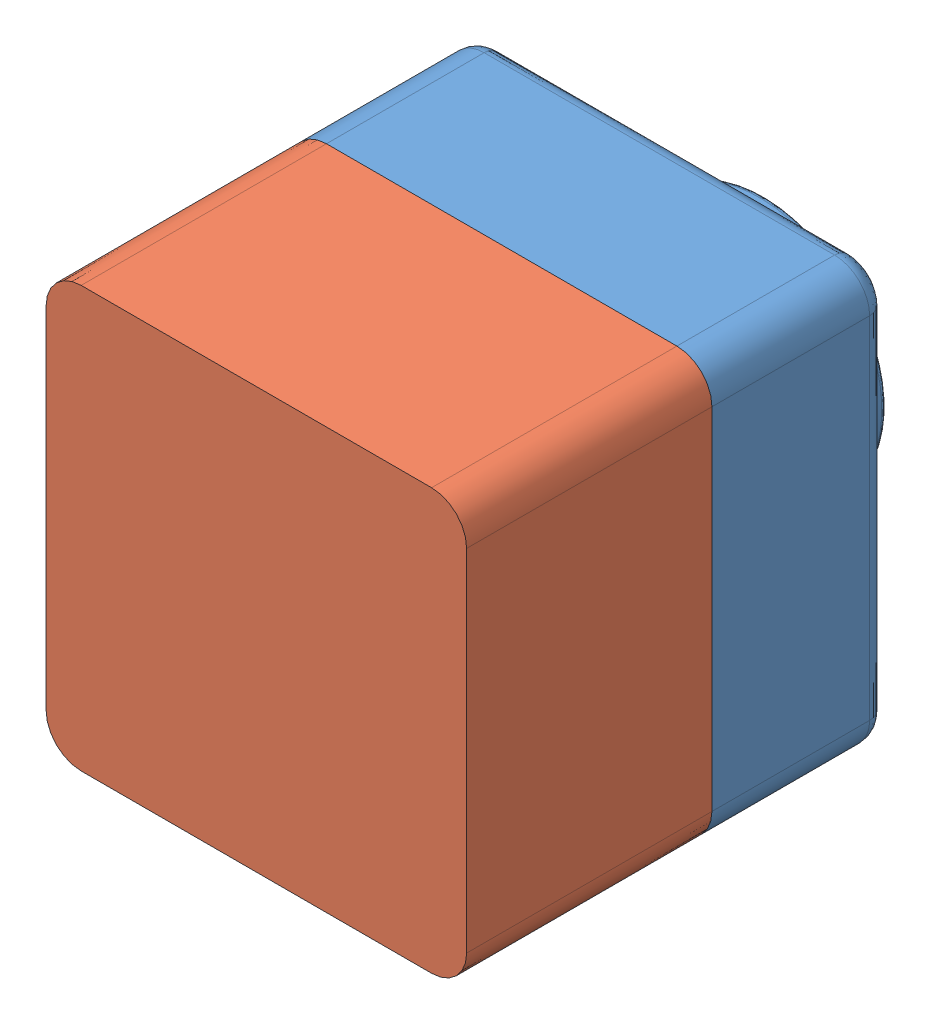
SolidWorks assembly Assem1, configuration Default. Lengths in mm.
Overall size (120 120 145).
2 component instances, 2 part files, 3 mates.
Components (placement in the parent):
- Part1-1: Part1 [Default] at (1.3944 79.59 90.9836) size (120 120 75)
- part2-2: part2 [Default] at (4.8079 98.2333 210.9836) x (-1 0 0) z (0 0 -1) size (120 120 90)
Mates (geometry in assembly coordinates):
- Coincident3: coincident: plane of Part1-1 through (-58.6056 137.59 140.9836) normal (0 -1 0); plane of part2-2 through (-48.6056 137.59 140.9836) normal (0 1 0)
- Coincident4: coincident: plane of Part1-1 through (-56.6056 139.59 140.9836) normal (1 0 0); plane of part2-2 through (-56.6056 29.59 140.9836) normal (-1 0 0)
- Coincident5: coincident anti-aligned: plane of Part1-1 through (1.3944 79.59 140.9836) normal (0 0 1); plane of part2-2 through (51.3944 129.59 140.9836) normal (0 0 -1)
